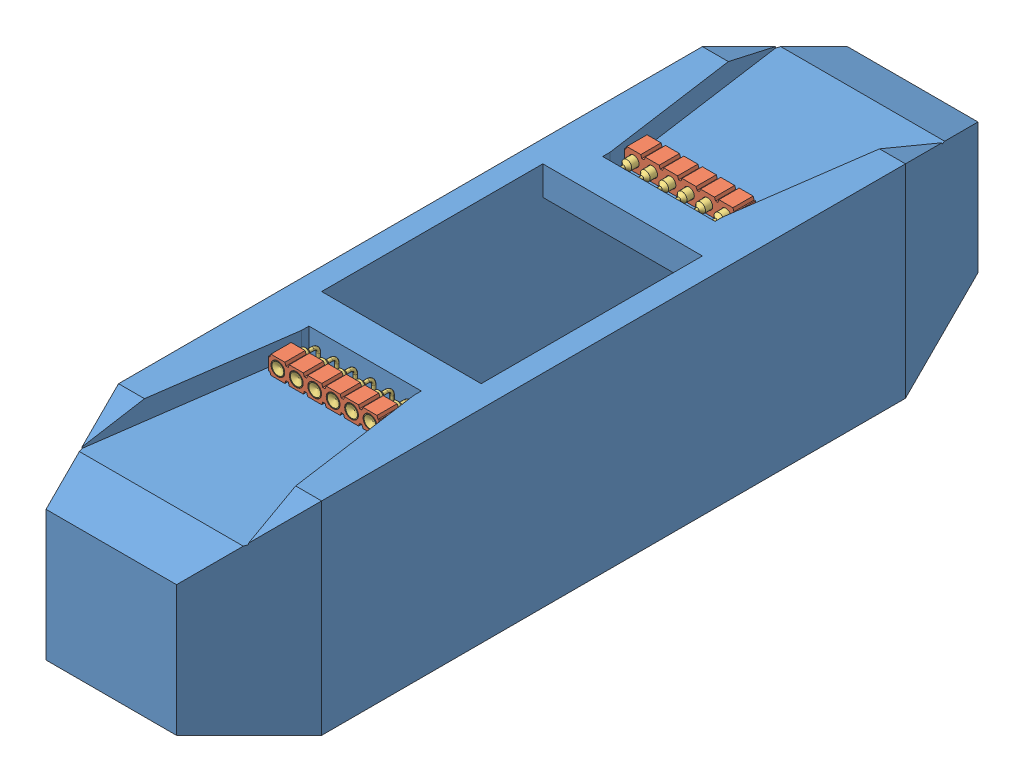
SolidWorks assembly Module_Battery, configuration Default. Lengths in mm.
Overall size (28 28 110.5).
17 component instances, 3 part files, 14 mates.
Components (placement in the parent):
- Module - RB_Gears-1: Module - RB_Gears [Battery] at (37.8746 66.7149 80.4494) size (28 28 110.5)
- mill-max-399-10-106-10-007000-1: mill-max-399-10-106-10-007000 [Default] at (87.4391 79.2849 107.5811) x (1 0 0) z (0 -1 0) size (15.24 5.81 5.74)
  - mill-max-399-10-106-10-007000_P3XX-11-010-00-000000(P306-11-010-00-000000)-1: mill-max-399-10-106-10-007000_P3XX-11-010-00-000000(P306-11-010-00-000000) [Default] at (-56.7488 -1.0694 1.27) size (15.24 2.79 2.54)
  - mill-max-399-10-106-10-007000_1960(1960-0-00-15-00-00-03-0)-1: mill-max-399-10-106-10-007000_1960(1960-0-00-15-00-00-03-0) [Default] at (-50.7044 -1.0694 0) x (0 -1 0) z (1 0 0) size (5.81 5.38 1.83)
  - mill-max-399-10-106-10-007000_1960(1960-0-00-15-00-00-03-0)-2: mill-max-399-10-106-10-007000_1960(1960-0-00-15-00-00-03-0) [Default] at (-43.0844 -1.0694 0) x (0 -1 0) z (1 0 0) size (5.81 5.38 1.83)
  - mill-max-399-10-106-10-007000_1960(1960-0-00-15-00-00-03-0)-3: mill-max-399-10-106-10-007000_1960(1960-0-00-15-00-00-03-0) [Default] at (-55.7844 -1.0694 0) x (0 -1 0) z (1 0 0) size (5.81 5.38 1.83)
  - mill-max-399-10-106-10-007000_1960(1960-0-00-15-00-00-03-0)-4: mill-max-399-10-106-10-007000_1960(1960-0-00-15-00-00-03-0) [Default] at (-48.1644 -1.0694 0) x (0 -1 0) z (1 0 0) size (5.81 5.38 1.83)
  - mill-max-399-10-106-10-007000_1960(1960-0-00-15-00-00-03-0)-5: mill-max-399-10-106-10-007000_1960(1960-0-00-15-00-00-03-0) [Default] at (-53.2444 -1.0694 0) x (0 -1 0) z (1 0 0) size (5.81 5.38 1.83)
  - mill-max-399-10-106-10-007000_1960(1960-0-00-15-00-00-03-0)-6: mill-max-399-10-106-10-007000_1960(1960-0-00-15-00-00-03-0) [Default] at (-45.6244 -1.0694 0) x (0 -1 0) z (1 0 0) size (5.81 5.38 1.83)
- mill-max-399-10-106-10-007000-2: mill-max-399-10-106-10-007000 [Default] at (-11.6898 79.2849 53.3178) x (-1 0 0) z (0 -1 0) size (15.24 5.81 5.74)
  - mill-max-399-10-106-10-007000_P3XX-11-010-00-000000(P306-11-010-00-000000)-1: mill-max-399-10-106-10-007000_P3XX-11-010-00-000000(P306-11-010-00-000000) [Default] at (-56.7488 -1.0694 1.27) size (15.24 2.79 2.54)
  - mill-max-399-10-106-10-007000_1960(1960-0-00-15-00-00-03-0)-1: mill-max-399-10-106-10-007000_1960(1960-0-00-15-00-00-03-0) [Default] at (-50.7044 -1.0694 0) x (0 -1 0) z (1 0 0) size (5.81 5.38 1.83)
  - mill-max-399-10-106-10-007000_1960(1960-0-00-15-00-00-03-0)-2: mill-max-399-10-106-10-007000_1960(1960-0-00-15-00-00-03-0) [Default] at (-43.0844 -1.0694 0) x (0 -1 0) z (1 0 0) size (5.81 5.38 1.83)
  - mill-max-399-10-106-10-007000_1960(1960-0-00-15-00-00-03-0)-3: mill-max-399-10-106-10-007000_1960(1960-0-00-15-00-00-03-0) [Default] at (-55.7844 -1.0694 0) x (0 -1 0) z (1 0 0) size (5.81 5.38 1.83)
  - mill-max-399-10-106-10-007000_1960(1960-0-00-15-00-00-03-0)-4: mill-max-399-10-106-10-007000_1960(1960-0-00-15-00-00-03-0) [Default] at (-48.1644 -1.0694 0) x (0 -1 0) z (1 0 0) size (5.81 5.38 1.83)
  - mill-max-399-10-106-10-007000_1960(1960-0-00-15-00-00-03-0)-5: mill-max-399-10-106-10-007000_1960(1960-0-00-15-00-00-03-0) [Default] at (-53.2444 -1.0694 0) x (0 -1 0) z (1 0 0) size (5.81 5.38 1.83)
  - mill-max-399-10-106-10-007000_1960(1960-0-00-15-00-00-03-0)-6: mill-max-399-10-106-10-007000_1960(1960-0-00-15-00-00-03-0) [Default] at (-45.6244 -1.0694 0) x (0 -1 0) z (1 0 0) size (5.81 5.38 1.83)
Mates (geometry in assembly coordinates):
- Coincident1: coincident anti-aligned: plane of Module - RB_Gears-1 through (37.8746 66.7149 26.6994) normal (0 0 1); plane of ? through (43.8746 71.7149 26.6994) normal (0 0 -1)
- Coincident2: coincident anti-aligned: plane of Module - RB_Gears-1 through (37.8746 66.7149 134.1994) normal (0 0 -1); plane of ? through (31.8746 71.7149 134.1994) normal (0 0 1)
- Concentric1: concentric anti-aligned: cylinder of Module - RB_Gears-1 through (37.8746 66.7149 20.9568) axis (0 0 1) radius 1.5; cylinder of ? through (37.8746 66.7149 22.1994) axis (0 0 -1) radius 1.5
- Concentric2: concentric aligned: cylinder of Module - RB_Gears-1 through (42.3746 66.7149 20.9568) axis (0 0 1) radius 0.95; cylinder of ? through (42.3746 66.7149 27.0994) axis (0 0 1) radius 0.8
- Concentric3: concentric anti-aligned: cylinder of Module - RB_Gears-1 through (37.8746 66.7149 139.9421) axis (0 0 -1) radius 1.5; cylinder of ? through (37.8746 66.7149 138.6994) axis (0 0 1) radius 1.5
- Concentric4: concentric aligned: cylinder of Module - RB_Gears-1 through (42.3746 66.7149 139.9421) axis (0 0 -1) radius 0.95; cylinder of ? through (42.3746 66.7149 133.7994) axis (0 0 -1) radius 0.8
- Tangent1: tangent anti-aligned: plane of Module - RB_Gears-1 through (45.6246 78.0149 100.6994) normal (0 0 1); cylinder of mill-max-399-10-106-10-007000-1/mill-max-399-10-106-10-007000_1960(1960-0-00-15-00-00-03-0)-2 through (44.3546 84.5216 100.928) axis (0 1 0) radius 0.2286
- Tangent2: tangent anti-aligned: plane of Module - RB_Gears-1 through (45.6246 78.0149 100.6994) normal (0 0 1); cylinder of mill-max-399-10-106-10-007000-1/mill-max-399-10-106-10-007000_1960(1960-0-00-15-00-00-03-0)-3 through (31.6546 84.5216 100.928) axis (0 1 0) radius 0.2286
- Tangent3: tangent anti-aligned: plane of Module - RB_Gears-1 through (45.6246 78.0149 60.1994) normal (0 0 -1); cylinder of mill-max-399-10-106-10-007000-2/mill-max-399-10-106-10-007000_1960(1960-0-00-15-00-00-03-0)-2 through (31.3946 84.5216 59.9708) axis (0 1 0) radius 0.2286
- Tangent4: tangent anti-aligned: plane of Module - RB_Gears-1 through (45.6246 78.0149 60.1994) normal (0 0 -1); cylinder of mill-max-399-10-106-10-007000-2/mill-max-399-10-106-10-007000_1960(1960-0-00-15-00-00-03-0)-3 through (44.0946 84.5216 59.9708) axis (0 1 0) radius 0.2286
- Coincident3: coincident anti-aligned: plane of Module - RB_Gears-1 through (37.8746 78.0149 80.4494) normal (0 1 0); plane of mill-max-399-10-106-10-007000-2/mill-max-399-10-106-10-007000_P3XX-11-010-00-000000(P306-11-010-00-000000)-1 through (45.059 78.0149 57.1811) normal (0 -1 0)
- Coincident4: coincident anti-aligned: plane of Module - RB_Gears-1 through (37.8746 78.0149 80.4494) normal (0 1 0); plane of mill-max-399-10-106-10-007000-1/mill-max-399-10-106-10-007000_P3XX-11-010-00-000000(P306-11-010-00-000000)-1 through (30.6903 78.0149 103.7177) normal (0 -1 0)
- Coincident5: coincident anti-aligned: plane of Module - RB_Gears-1 through (45.6246 78.0149 120.6994) normal (-1 0 0); plane of mill-max-399-10-106-10-007000-1/mill-max-399-10-106-10-007000_P3XX-11-010-00-000000(P306-11-010-00-000000)-1 through (45.6246 80.1549 103.7177) normal (1 0 0)
- Coincident7: coincident anti-aligned: plane of Module - RB_Gears-1 through (30.1246 78.0149 40.1994) normal (1 0 0); plane of mill-max-399-10-106-10-007000-2/mill-max-399-10-106-10-007000_P3XX-11-010-00-000000(P306-11-010-00-000000)-1 through (30.1246 80.1549 57.1811) normal (-1 0 0)
